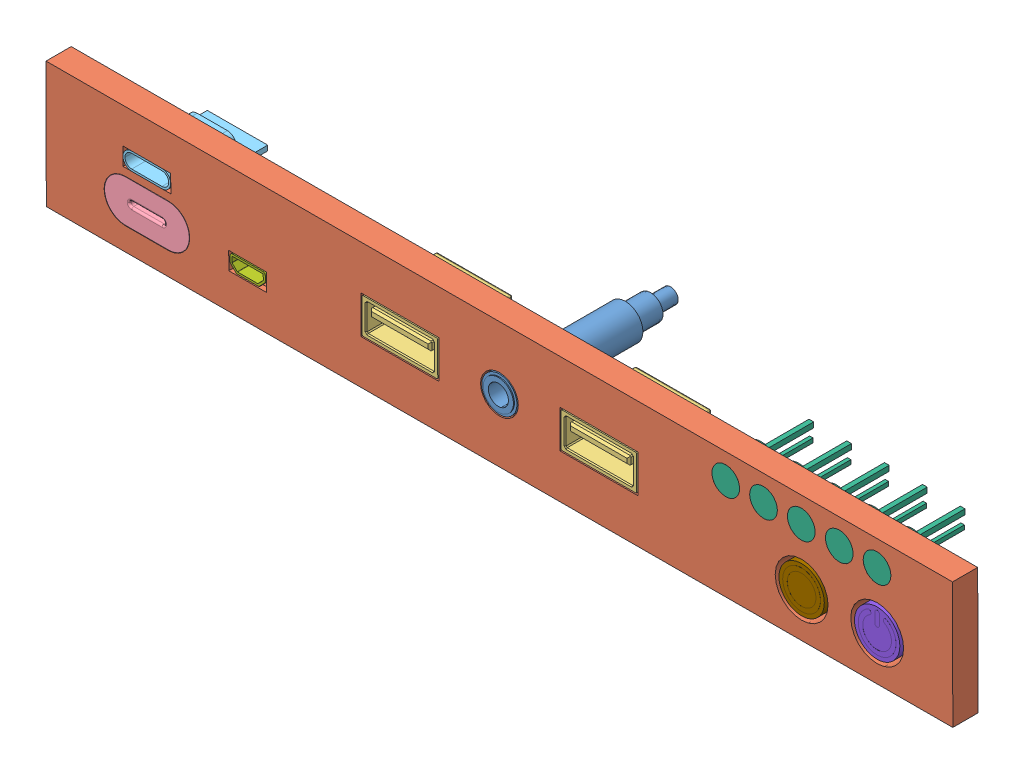
SolidWorks assembly FrontIO, configuration Default. Lengths in mm.
Overall size (180.06 25.43 34.2).
14 component instances, 9 part files, 26 mates.
Components (placement in the parent):
- aux-jack-1: aux-jack [Default] at (22.4107 22.4035 9.9667) size (7 7 34.2)
- Front-1: Front [Default] at (22.4107 22.4035 29.9667) x (0.999997 0.002406 0) z (0.002406 -0.999997 0) size (180 5 25)
- USB-Port-1: USB-Port [Default] at (42.1606 22.451 19.9667) x (0.999997 0.002406 0) z (0 0 1) size (15 7 15)
- USB-Port-2: USB-Port [Default] at (2.6608 22.356 19.9667) x (0.999997 0.002406 0) z (0 0 1) size (15 7 15)
- Lightning-c-1: Lightning-c [Default] at (-51.7901 21.1486 19.9667) x (0.999997 0.002406 0) z (0 0 1) size (17 8.5 15)
- usb-c-port-1: usb-c-port [Default] at (-47.5981 25.9851 21.9667) x (0.999997 0.002406 0) z (0 0 1) size (12 4.5 18)
- LeD-1: LeD [Default] at (97.3924 30.0839 28.9667) size (6.5 6.5 17)
- LeD-2: LeD [Default] at (89.8925 30.0659 28.9667) size (6.5 6.5 17)
- LeD-3: LeD [Default] at (82.3501 30.0477 28.9667) size (6.5 6.5 17)
- LeD-4: LeD [Default] at (74.8501 30.0297 28.9667) size (6.5 6.5 17)
- LeD-5: LeD [Default] at (67.3501 30.0116 28.9667) size (6.5 6.5 17)
- USB-b-1: USB-b [Default] at (-27.5801 18.5332 28.9667) x (0.999997 0.002406 0) z (0 0 1) size (11 4 9)
- PWR-1: PWR [Default] at (97.4195 18.8339 31.9667) size (9 9 9.01)
- CHG-1: CHG [Default] at (82.4195 18.7979 31.9667) size (9 9 9.01)
Mates (geometry in assembly coordinates):
- Concentric1: concentric: circle of aux-jack-1; circle of Front-1
- Coincident1: coincident: plane of aux-jack-1 through (22.4107 22.4035 34.9667) normal (0 0 1); plane of Front-1 through (22.4107 22.4035 34.9667) normal (0 0 1)
- Distance4: distance = 0.25 mm: plane of Front-1 through (-5.0802 18.5874 34.9667) normal (-0.002406 0.999997 0); plane of USB-Port-2 through (-4.8308 18.838 34.9667) normal (0.002406 -0.999997 0)
- Distance3: distance = 0.25 mm: plane of Front-1 through (49.9196 18.7197 34.9667) normal (-0.002406 0.999997 0); plane of USB-Port-1 through (34.6691 18.933 34.9667) normal (0.002406 -0.999997 0)
- Distance2: distance = 0.25 mm: plane of Front-1 through (10.4198 18.6246 34.9667) normal (-0.999997 -0.002406 0); plane of USB-Port-2 through (10.1523 25.874 34.9667) normal (0.999997 0.002406 0)
- Distance1: distance = 0.25 mm: plane of Front-1 through (49.9196 18.7197 34.9667) normal (-0.999997 -0.002406 0); plane of USB-Port-1 through (49.6522 25.969 34.9667) normal (0.999997 0.002406 0)
- Coincident6: coincident: plane of Front-1 through (22.4107 22.4035 34.9667) normal (0 0 1); plane of USB-Port-1 through (42.1606 22.451 34.9667) normal (0 0 1)
- Coincident7: coincident: plane of Front-1 through (22.4107 22.4035 34.9667) normal (0 0 1); plane of USB-Port-2 through (2.6608 22.356 34.9667) normal (0 0 1)
- Coincident8: coincident: plane of Front-1 through (22.4107 22.4035 34.9667) normal (0 0 1); plane of Lightning-c-1 through (-43.3291 18.5185 34.9667) normal (0 0 1)
- Coincident9: coincident: plane of Front-1 through (-51.8199 14.2471 34.9667) normal (-0.002406 0.999997 0); plane of Lightning-c-1 through (-51.8209 14.2471 34.9667) normal (0.002406 -0.999997 0)
- Coincident10: coincident: cylinder of Front-1 through (-43.3301 18.5175 34.9667) axis (0 0 -1) radius 4.25; line of Lightning-c-1 through (-39.0802 18.5288 34.8667) axis (0 0 -1)
- Coincident11: coincident: plane of Front-1 through (22.4107 22.4035 34.9667) normal (0 0 1); plane of usb-c-port-1 through (-44.5971 25.9933 34.9667) normal (0 0 1)
- Coincident12: coincident: plane of Front-1 through (-52.3439 24.2237 34.9667) normal (-0.002406 0.999997 0); plane of usb-c-port-1 through (-50.5949 24.2279 34.9667) normal (0.002406 -0.999997 0)
- Coincident13: coincident: plane of Front-1 through (-42.8439 24.2465 34.9667) normal (-0.999997 -0.002406 0); line of usb-c-port-1 through (-42.8481 25.9975 34.9667) axis (0 0 -1)
- Coincident14: coincident: circle of Front-1; circle of LeD-1
- Coincident15: coincident: circle of Front-1; circle of LeD-2
- Coincident16: coincident: circle of Front-1; circle of LeD-3
- Coincident17: coincident: circle of Front-1; circle of LeD-4
- Coincident18: coincident: circle of Front-1; circle of LeD-5
- Coincident19: coincident: plane of Front-1 through (22.4107 22.4035 34.9667) normal (0 0 1); plane of USB-b-1 through (-27.5801 18.5332 34.9667) normal (0 0 1)
- Distance5: distance = 0.25 mm: plane of USB-b-1 through (-31.0837 20.0248 34.9667) normal (-0.999997 -0.002406 0); plane of Front-1 through (-31.3259 16.7742 34.9667) normal (0.999997 0.002406 0)
- Distance6: distance = 0.25 mm: plane of USB-b-1 through (-31.0837 20.0248 34.9667) normal (-0.002406 0.999997 0); plane of Front-1 through (-31.3343 20.2742 34.9667) normal (0.002406 -0.999997 0)
- Coincident20: coincident: plane of Front-1 through (22.4107 22.4035 34.9667) normal (0 0 1); plane of CHG-1 through (82.4195 18.7979 34.9667) normal (0 0 1)
- Concentric2: concentric: circle of Front-1; circle of CHG-1
- Concentric3: concentric: circle of Front-1; circle of PWR-1
- Coincident21: coincident: plane of Front-1 through (22.4107 22.4035 34.9667) normal (0 0 1); plane of PWR-1 through (97.4195 18.8339 34.9667) normal (0 0 1)
